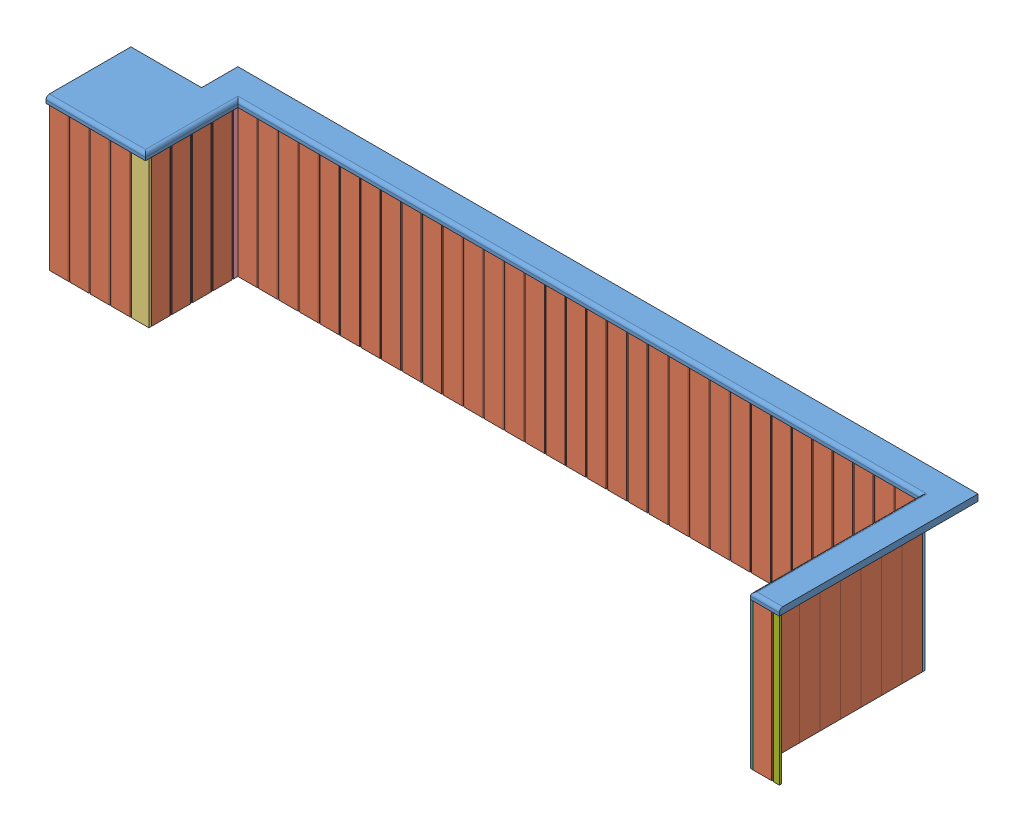
SolidWorks assembly Brüstung, configuration Standard. Lengths in mm.
Overall size (4774 900 1170).
56 component instances, 7 part files, 166 mates.
Components (placement in the parent):
- Platte-1: Platte [Standard] at (1989.1315 795.0064 4189) size (4774 38 1170)
- Wandbrett-1: Wandbrett [Standard] at (-2724.3685 795.0064 4876) x (1 0 0) z (0 0 -1) size (131 862 14)
- Wandbrett-2: Wandbrett [Standard] at (-2603.3685 795.0064 4876) x (1 0 0) z (0 0 -1) size (131 862 14)
- Wandbrett-3: Wandbrett [Standard] at (-2482.3685 795.0064 4876) x (1 0 0) z (0 0 -1) size (131 862 14)
- Wandbrett-4: Wandbrett [Standard] at (-2361.3685 795.0064 4876) x (1 0 0) z (0 0 -1) size (131 862 14)
- Wandbrett-Ecke1-1: Wandbrett-Ecke1 [Standard] at (-2240.3685 795.0064 4876) x (1 0 0) z (0 0 -1) size (102 862 14)
- Wandbrett-6: Wandbrett [Standard] at (-2205.8685 795.0064 4808.5) x (0 0 -1) z (-1 0 0) size (131 862 14)
- Wandbrett-7: Wandbrett [Standard] at (-2205.8685 795.0064 4687.5) x (0 0 -1) z (-1 0 0) size (131 862 14)
- Wandbrett-8: Wandbrett [Standard] at (-2205.8685 795.0064 4566.5) x (0 0 -1) z (-1 0 0) size (131 862 14)
- Wandbrett-9: Wandbrett [Standard] at (-2205.8685 795.0064 4445.5) x (0 0 -1) z (-1 0 0) size (131 862 14)
- Wandbrett-Ecke2-1: Wandbrett-Ecke2 [Standard] at (-2205.8685 795.0064 4324.5) x (0 0 -1) z (-1 0 0) size (60 862 14)
- Wandbrett-11: Wandbrett [Standard] at (-2138.3685 795.0064 4352) x (1 0 0) z (0 0 -1) size (131 862 14)
- Wandbrett-12: Wandbrett [Standard] at (-2017.3685 795.0064 4352) x (1 0 0) z (0 0 -1) size (131 862 14)
- Wandbrett-13: Wandbrett [Standard] at (-1896.3685 795.0064 4352) x (1 0 0) z (0 0 -1) size (131 862 14)
- Wandbrett-14: Wandbrett [Standard] at (-1775.3685 795.0064 4352) x (1 0 0) z (0 0 -1) size (131 862 14)
- Wandbrett-15: Wandbrett [Standard] at (-1654.3685 795.0064 4352) x (1 0 0) z (0 0 -1) size (131 862 14)
- Wandbrett-16: Wandbrett [Standard] at (-1533.3685 795.0064 4352) x (1 0 0) z (0 0 -1) size (131 862 14)
- Wandbrett-17: Wandbrett [Standard] at (-1412.3685 795.0064 4352) x (1 0 0) z (0 0 -1) size (131 862 14)
- Wandbrett-18: Wandbrett [Standard] at (-1291.3685 795.0064 4352) x (1 0 0) z (0 0 -1) size (131 862 14)
- Wandbrett-19: Wandbrett [Standard] at (-1170.3685 795.0064 4352) x (1 0 0) z (0 0 -1) size (131 862 14)
- Wandbrett-20: Wandbrett [Standard] at (-1049.3685 795.0064 4352) x (1 0 0) z (0 0 -1) size (131 862 14)
- Wandbrett-21: Wandbrett [Standard] at (-928.3685 795.0064 4352) x (1 0 0) z (0 0 -1) size (131 862 14)
- Wandbrett-22: Wandbrett [Standard] at (-807.3685 795.0064 4352) x (1 0 0) z (0 0 -1) size (131 862 14)
- Wandbrett-23: Wandbrett [Standard] at (-686.3685 795.0064 4352) x (1 0 0) z (0 0 -1) size (131 862 14)
- Wandbrett-24: Wandbrett [Standard] at (-565.3685 795.0064 4352) x (1 0 0) z (0 0 -1) size (131 862 14)
- Wandbrett-25: Wandbrett [Standard] at (-444.3685 795.0064 4352) x (1 0 0) z (0 0 -1) size (131 862 14)
- Wandbrett-26: Wandbrett [Standard] at (-323.3685 795.0064 4352) x (1 0 0) z (0 0 -1) size (131 862 14)
- Wandbrett-27: Wandbrett [Standard] at (-202.3685 795.0064 4352) x (1 0 0) z (0 0 -1) size (131 862 14)
- Wandbrett-28: Wandbrett [Standard] at (-81.3685 795.0064 4352) x (1 0 0) z (0 0 -1) size (131 862 14)
- Wandbrett-29: Wandbrett [Standard] at (39.6315 795.0064 4352) x (1 0 0) z (0 0 -1) size (131 862 14)
- Wandbrett-30: Wandbrett [Standard] at (160.6315 795.0064 4352) x (1 0 0) z (0 0 -1) size (131 862 14)
- Wandbrett-31: Wandbrett [Standard] at (281.6315 795.0064 4352) x (1 0 0) z (0 0 -1) size (131 862 14)
- Wandbrett-32: Wandbrett [Standard] at (402.6315 795.0064 4352) x (1 0 0) z (0 0 -1) size (131 862 14)
- Wandbrett-33: Wandbrett [Standard] at (523.6315 795.0064 4352) x (1 0 0) z (0 0 -1) size (131 862 14)
- Wandbrett-34: Wandbrett [Standard] at (644.6315 795.0064 4352) x (1 0 0) z (0 0 -1) size (131 862 14)
- Wandbrett-35: Wandbrett [Standard] at (765.6315 795.0064 4352) x (1 0 0) z (0 0 -1) size (131 862 14)
- Wandbrett-36: Wandbrett [Standard] at (886.6315 795.0064 4352) x (1 0 0) z (0 0 -1) size (131 862 14)
- Wandbrett-37: Wandbrett [Standard] at (1007.6315 795.0064 4352) x (1 0 0) z (0 0 -1) size (131 862 14)
- Wandbrett-38: Wandbrett [Standard] at (1128.6315 795.0064 4352) x (1 0 0) z (0 0 -1) size (131 862 14)
- Wandbrett-39: Wandbrett [Standard] at (1249.6315 795.0064 4352) x (1 0 0) z (0 0 -1) size (131 862 14)
- Wandbrett-40: Wandbrett [Standard] at (1370.6315 795.0064 4352) x (1 0 0) z (0 0 -1) size (131 862 14)
- Wandbrett-41: Wandbrett [Standard] at (1491.6315 795.0064 4352) x (1 0 0) z (0 0 -1) size (131 862 14)
- Wandbrett-42: Wandbrett [Standard] at (1612.6315 795.0064 4352) x (1 0 0) z (0 0 -1) size (131 862 14)
- Wandbrett-43: Wandbrett [Standard] at (1733.6315 795.0064 4352) x (1 0 0) z (0 0 -1) size (131 862 14)
- Wandbrett-Ecke3-1: Wandbrett-Ecke3 [Standard] at (1854.6315 795.0064 4352) x (1 0 0) z (0 0 -1) size (39 862 14)
- Wandbrett-44: Wandbrett [Standard] at (1826.1315 795.0064 4419.5) x (0 0 1) z (1 0 0) size (131 862 14)
- Wandbrett-45: Wandbrett [Standard] at (1826.1315 795.0064 4540.5) x (0 0 1) z (1 0 0) size (131 862 14)
- Wandbrett-46: Wandbrett [Standard] at (1826.1315 795.0064 4661.5) x (0 0 1) z (1 0 0) size (131 862 14)
- Wandbrett-47: Wandbrett [Standard] at (1826.1315 795.0064 4782.5) x (0 0 1) z (1 0 0) size (131 862 14)
- Wandbrett-48: Wandbrett [Standard] at (1826.1315 795.0064 4903.5) x (0 0 1) z (1 0 0) size (131 862 14)
- Wandbrett-49: Wandbrett [Standard] at (1826.1315 795.0064 5024.5) x (0 0 1) z (1 0 0) size (131 862 14)
- Wandbrett-50: Wandbrett [Standard] at (1826.1315 795.0064 5145.5) x (0 0 1) z (1 0 0) size (131 862 14)
- Wandbrett-51: Wandbrett [Standard] at (1826.1315 795.0064 5266.5) x (0 0 1) z (1 0 0) size (131 862 14)
- Wandbrett-Ecke4-1: Wandbrett-Ecke4 [Standard] at (1826.1315 795.0064 5387.5) x (0 0 1) z (1 0 0) size (32 862 14)
- Wandbrett-52: Wandbrett [Standard] at (1893.6315 795.0064 5352) x (1 0 0) z (0 0 -1) size (131 862 14)
- Wandbrett-Ecke5-1: Wandbrett-Ecke5 [Standard] at (2014.6315 795.0064 5352) x (1 0 0) z (0 0 -1) size (35 862 14)
Mates (geometry in assembly coordinates):
- Deckungsgleich1: coincident anti-aligned: plane of Platte-1 through (1989.1315 795.0064 4189) normal (0 -1 0); plane of Wandbrett-1 through (-2674.8685 795.0064 4879) normal (0 1 0)
- Deckungsgleich2: coincident anti-aligned: plane of Platte-1 through (1989.1315 795.0064 4189) normal (0 -1 0); plane of Wandbrett-2 through (-2553.8685 795.0064 4879) normal (0 1 0)
- Deckungsgleich3: coincident anti-aligned: plane of Platte-1 through (1989.1315 795.0064 4189) normal (0 -1 0); plane of Wandbrett-3 through (-2432.8685 795.0064 4879) normal (0 1 0)
- Deckungsgleich4: coincident anti-aligned: plane of Platte-1 through (1989.1315 795.0064 4189) normal (0 -1 0); plane of Wandbrett-4 through (-2311.8685 795.0064 4879) normal (0 1 0)
- Parallel1: parallel aligned: plane of Platte-1 through (-2784.8685 833.0064 4903) normal (0 0 1); plane of Wandbrett-1 through (-2674.8685 -66.9936 4883) normal (0 0 1)
- Abstand2: distance = 20 mm aligned: plane of Wandbrett-1 through (-2674.8685 -66.9936 4883) normal (0 0 1); plane of Platte-1 through (-2784.8685 833.0064 4903) normal (0 0 1)
- Deckungsgleich9: coincident aligned: plane of Platte-1 through (-2784.8685 833.0064 4903) normal (-1 0 0); plane of Wandbrett-1 through (-2784.8685 -66.9936 4869) normal (-1 0 0)
- Deckungsgleich10: coincident anti-aligned: plane of Wandbrett-1 through (-2663.8685 -66.9936 4878) normal (0 0 1); plane of Wandbrett-2 through (-2653.8685 -66.9936 4878) normal (0 0 -1)
- Deckungsgleich11: coincident anti-aligned: plane of Wandbrett-2 through (-2542.8685 -66.9936 4878) normal (0 0 1); plane of Wandbrett-3 through (-2532.8685 -66.9936 4878) normal (0 0 -1)
- Deckungsgleich12: coincident anti-aligned: plane of Wandbrett-3 through (-2421.8685 -66.9936 4878) normal (0 0 1); plane of Wandbrett-4 through (-2411.8685 -66.9936 4878) normal (0 0 -1)
- Deckungsgleich14: coincident anti-aligned: plane of Wandbrett-1 through (-2653.8685 -66.9936 4878) normal (1 0 0); plane of Wandbrett-2 through (-2653.8685 -66.9936 4874) normal (-1 0 0)
- Deckungsgleich15: coincident anti-aligned: plane of Wandbrett-2 through (-2532.8685 -66.9936 4878) normal (1 0 0); plane of Wandbrett-3 through (-2532.8685 -66.9936 4874) normal (-1 0 0)
- Deckungsgleich16: coincident anti-aligned: plane of Wandbrett-3 through (-2411.8685 -66.9936 4878) normal (1 0 0); plane of Wandbrett-4 through (-2411.8685 -66.9936 4874) normal (-1 0 0)
- Deckungsgleich18: coincident anti-aligned: plane of Platte-1 through (1989.1315 795.0064 4189) normal (0 -1 0); plane of Wandbrett-Ecke1-1 through (-2190.8685 795.0064 4879) normal (0 1 0)
- Deckungsgleich19: coincident anti-aligned: plane of Wandbrett-4 through (-2300.8685 -66.9936 4878) normal (0 0 1); plane of Wandbrett-Ecke1-1 through (-2290.8685 -66.9936 4878) normal (0 0 -1)
- Deckungsgleich20: coincident anti-aligned: plane of Wandbrett-4 through (-2290.8685 -66.9936 4878) normal (1 0 0); plane of Wandbrett-Ecke1-1 through (-2290.8685 -66.9936 4874) normal (-1 0 0)
- Deckungsgleich21: coincident anti-aligned: plane of Platte-1 through (1989.1315 795.0064 4189) normal (0 -1 0); plane of Wandbrett-6 through (-2202.8685 795.0064 4759) normal (0 1 0)
- Deckungsgleich22: coincident anti-aligned: plane of Platte-1 through (1989.1315 795.0064 4189) normal (0 -1 0); plane of Wandbrett-7 through (-2202.8685 795.0064 4638) normal (0 1 0)
- Deckungsgleich23: coincident anti-aligned: plane of Platte-1 through (1989.1315 795.0064 4189) normal (0 -1 0); plane of Wandbrett-8 through (-2202.8685 795.0064 4517) normal (0 1 0)
- Deckungsgleich24: coincident anti-aligned: plane of Platte-1 through (1989.1315 795.0064 4189) normal (0 -1 0); plane of Wandbrett-9 through (-2202.8685 795.0064 4396) normal (0 1 0)
- Deckungsgleich26: coincident anti-aligned: plane of Wandbrett-Ecke1-1 through (-2179.8685 -66.9936 4869) normal (0 0 -1); plane of Wandbrett-6 through (-2212.8685 -66.9936 4869) normal (0 0 1)
- Deckungsgleich27: coincident aligned: plane of Platte-1 through (-2198.8685 833.0064 4359) normal (1 0 0); plane of Wandbrett-6 through (-2198.8685 -66.9936 4759) normal (1 0 0)
- Deckungsgleich28: coincident anti-aligned: plane of Wandbrett-6 through (-2203.8685 -66.9936 4748) normal (1 0 0); plane of Wandbrett-7 through (-2203.8685 -66.9936 4738) normal (-1 0 0)
- Deckungsgleich29: coincident anti-aligned: plane of Wandbrett-7 through (-2203.8685 -66.9936 4627) normal (1 0 0); plane of Wandbrett-8 through (-2203.8685 -66.9936 4617) normal (-1 0 0)
- Deckungsgleich30: coincident anti-aligned: plane of Wandbrett-8 through (-2203.8685 -66.9936 4506) normal (1 0 0); plane of Wandbrett-9 through (-2203.8685 -66.9936 4496) normal (-1 0 0)
- Deckungsgleich32: coincident anti-aligned: plane of Wandbrett-6 through (-2203.8685 -66.9936 4738) normal (0 0 -1); plane of Wandbrett-7 through (-2207.8685 -66.9936 4738) normal (0 0 1)
- Deckungsgleich33: coincident anti-aligned: plane of Wandbrett-7 through (-2203.8685 -66.9936 4617) normal (0 0 -1); plane of Wandbrett-8 through (-2207.8685 -66.9936 4617) normal (0 0 1)
- Deckungsgleich34: coincident anti-aligned: plane of Wandbrett-8 through (-2203.8685 -66.9936 4496) normal (0 0 -1); plane of Wandbrett-9 through (-2207.8685 -66.9936 4496) normal (0 0 1)
- Deckungsgleich36: coincident anti-aligned: plane of Platte-1 through (1989.1315 795.0064 4189) normal (0 -1 0); plane of Wandbrett-Ecke2-1 through (-2202.8685 795.0064 4275) normal (0 1 0)
- Deckungsgleich37: coincident anti-aligned: plane of Wandbrett-9 through (-2203.8685 -66.9936 4385) normal (1 0 0); plane of Wandbrett-Ecke2-1 through (-2203.8685 -66.9936 4375) normal (-1 0 0)
- Deckungsgleich38: coincident anti-aligned: plane of Wandbrett-9 through (-2203.8685 -66.9936 4375) normal (0 0 -1); plane of Wandbrett-Ecke2-1 through (-2207.8685 -66.9936 4375) normal (0 0 1)
- Deckungsgleich39: coincident anti-aligned: plane of Platte-1 through (1989.1315 795.0064 4189) normal (0 -1 0); plane of Wandbrett-11 through (-2088.8685 795.0064 4355) normal (0 1 0)
- Deckungsgleich40: coincident anti-aligned: plane of Platte-1 through (1989.1315 795.0064 4189) normal (0 -1 0); plane of Wandbrett-12 through (-1967.8685 795.0064 4355) normal (0 1 0)
- Deckungsgleich41: coincident anti-aligned: plane of Platte-1 through (1989.1315 795.0064 4189) normal (0 -1 0); plane of Wandbrett-13 through (-1846.8685 795.0064 4355) normal (0 1 0)
- Deckungsgleich42: coincident anti-aligned: plane of Platte-1 through (1989.1315 795.0064 4189) normal (0 -1 0); plane of Wandbrett-14 through (-1725.8685 795.0064 4355) normal (0 1 0)
- Deckungsgleich43: coincident anti-aligned: plane of Platte-1 through (1989.1315 795.0064 4189) normal (0 -1 0); plane of Wandbrett-15 through (-1604.8685 795.0064 4355) normal (0 1 0)
- Deckungsgleich44: coincident anti-aligned: plane of Platte-1 through (1989.1315 795.0064 4189) normal (0 -1 0); plane of Wandbrett-16 through (-1483.8685 795.0064 4355) normal (0 1 0)
- Deckungsgleich45: coincident anti-aligned: plane of Platte-1 through (1989.1315 795.0064 4189) normal (0 -1 0); plane of Wandbrett-17 through (-1362.8685 795.0064 4355) normal (0 1 0)
- Deckungsgleich46: coincident anti-aligned: plane of Platte-1 through (1989.1315 795.0064 4189) normal (0 -1 0); plane of Wandbrett-18 through (-1241.8685 795.0064 4355) normal (0 1 0)
- Deckungsgleich47: coincident anti-aligned: plane of Platte-1 through (1989.1315 795.0064 4189) normal (0 -1 0); plane of Wandbrett-19 through (-1120.8685 795.0064 4355) normal (0 1 0)
- Deckungsgleich48: coincident anti-aligned: plane of Platte-1 through (1989.1315 795.0064 4189) normal (0 -1 0); plane of Wandbrett-20 through (-999.8685 795.0064 4355) normal (0 1 0)
- Deckungsgleich49: coincident anti-aligned: plane of Platte-1 through (1989.1315 795.0064 4189) normal (0 -1 0); plane of Wandbrett-21 through (-878.8685 795.0064 4355) normal (0 1 0)
- Deckungsgleich50: coincident anti-aligned: plane of Platte-1 through (1989.1315 795.0064 4189) normal (0 -1 0); plane of Wandbrett-22 through (-757.8685 795.0064 4355) normal (0 1 0)
- Deckungsgleich51: coincident anti-aligned: plane of Platte-1 through (1989.1315 795.0064 4189) normal (0 -1 0); plane of Wandbrett-23 through (-636.8685 795.0064 4355) normal (0 1 0)
- Deckungsgleich52: coincident anti-aligned: plane of Platte-1 through (1989.1315 795.0064 4189) normal (0 -1 0); plane of Wandbrett-24 through (-515.8685 795.0064 4355) normal (0 1 0)
- Deckungsgleich53: coincident anti-aligned: plane of Platte-1 through (1989.1315 795.0064 4189) normal (0 -1 0); plane of Wandbrett-25 through (-394.8685 795.0064 4355) normal (0 1 0)
- Deckungsgleich54: coincident anti-aligned: plane of Platte-1 through (1989.1315 795.0064 4189) normal (0 -1 0); plane of Wandbrett-26 through (-273.8685 795.0064 4355) normal (0 1 0)
- Deckungsgleich55: coincident anti-aligned: plane of Platte-1 through (1989.1315 795.0064 4189) normal (0 -1 0); plane of Wandbrett-27 through (-152.8685 795.0064 4355) normal (0 1 0)
- Deckungsgleich56: coincident anti-aligned: plane of Platte-1 through (1989.1315 795.0064 4189) normal (0 -1 0); plane of Wandbrett-28 through (-31.8685 795.0064 4355) normal (0 1 0)
- Deckungsgleich57: coincident anti-aligned: plane of Platte-1 through (1989.1315 795.0064 4189) normal (0 -1 0); plane of Wandbrett-29 through (89.1315 795.0064 4355) normal (0 1 0)
- Deckungsgleich58: coincident anti-aligned: plane of Platte-1 through (1989.1315 795.0064 4189) normal (0 -1 0); plane of Wandbrett-30 through (210.1315 795.0064 4355) normal (0 1 0)
- Deckungsgleich59: coincident anti-aligned: plane of Platte-1 through (1989.1315 795.0064 4189) normal (0 -1 0); plane of Wandbrett-31 through (331.1315 795.0064 4355) normal (0 1 0)
- Deckungsgleich60: coincident anti-aligned: plane of Platte-1 through (1989.1315 795.0064 4189) normal (0 -1 0); plane of Wandbrett-32 through (452.1315 795.0064 4355) normal (0 1 0)
- Deckungsgleich61: coincident anti-aligned: plane of Platte-1 through (1989.1315 795.0064 4189) normal (0 -1 0); plane of Wandbrett-33 through (573.1315 795.0064 4355) normal (0 1 0)
- Deckungsgleich62: coincident anti-aligned: plane of Platte-1 through (1989.1315 795.0064 4189) normal (0 -1 0); plane of Wandbrett-34 through (694.1315 795.0064 4355) normal (0 1 0)
- Deckungsgleich63: coincident anti-aligned: plane of Platte-1 through (1989.1315 795.0064 4189) normal (0 -1 0); plane of Wandbrett-35 through (815.1315 795.0064 4355) normal (0 1 0)
- Deckungsgleich64: coincident anti-aligned: plane of Platte-1 through (1989.1315 795.0064 4189) normal (0 -1 0); plane of Wandbrett-36 through (936.1315 795.0064 4355) normal (0 1 0)
- Deckungsgleich65: coincident anti-aligned: plane of Platte-1 through (1989.1315 795.0064 4189) normal (0 -1 0); plane of Wandbrett-37 through (1057.1315 795.0064 4355) normal (0 1 0)
- Deckungsgleich66: coincident anti-aligned: plane of Platte-1 through (1989.1315 795.0064 4189) normal (0 -1 0); plane of Wandbrett-38 through (1178.1315 795.0064 4355) normal (0 1 0)
- Deckungsgleich67: coincident anti-aligned: plane of Platte-1 through (1989.1315 795.0064 4189) normal (0 -1 0); plane of Wandbrett-39 through (1299.1315 795.0064 4355) normal (0 1 0)
- Deckungsgleich68: coincident anti-aligned: plane of Platte-1 through (1989.1315 795.0064 4189) normal (0 -1 0); plane of Wandbrett-40 through (1420.1315 795.0064 4355) normal (0 1 0)
- Deckungsgleich69: coincident anti-aligned: plane of Platte-1 through (1989.1315 795.0064 4189) normal (0 -1 0); plane of Wandbrett-41 through (1541.1315 795.0064 4355) normal (0 1 0)
- Deckungsgleich70: coincident anti-aligned: plane of Platte-1 through (1989.1315 795.0064 4189) normal (0 -1 0); plane of Wandbrett-42 through (1662.1315 795.0064 4355) normal (0 1 0)
- Deckungsgleich71: coincident anti-aligned: plane of Wandbrett-Ecke2-1 through (-2198.8685 -66.9936 4275) normal (1 0 0); plane of Wandbrett-11 through (-2198.8685 -66.9936 4354) normal (-1 0 0)
- Deckungsgleich72: coincident anti-aligned: plane of Wandbrett-11 through (-2077.8685 -66.9936 4354) normal (0 0 1); plane of Wandbrett-12 through (-2067.8685 -66.9936 4354) normal (0 0 -1)
- Deckungsgleich73: coincident anti-aligned: plane of Wandbrett-12 through (-1956.8685 -66.9936 4354) normal (0 0 1); plane of Wandbrett-13 through (-1946.8685 -66.9936 4354) normal (0 0 -1)
- Deckungsgleich74: coincident anti-aligned: plane of Wandbrett-13 through (-1835.8685 -66.9936 4354) normal (0 0 1); plane of Wandbrett-14 through (-1825.8685 -66.9936 4354) normal (0 0 -1)
- Deckungsgleich75: coincident anti-aligned: plane of Wandbrett-14 through (-1714.8685 -66.9936 4354) normal (0 0 1); plane of Wandbrett-15 through (-1704.8685 -66.9936 4354) normal (0 0 -1)
- Deckungsgleich76: coincident anti-aligned: plane of Wandbrett-15 through (-1593.8685 -66.9936 4354) normal (0 0 1); plane of Wandbrett-16 through (-1583.8685 -66.9936 4354) normal (0 0 -1)
- Deckungsgleich77: coincident anti-aligned: plane of Wandbrett-16 through (-1472.8685 -66.9936 4354) normal (0 0 1); plane of Wandbrett-17 through (-1462.8685 -66.9936 4354) normal (0 0 -1)
- Deckungsgleich78: coincident anti-aligned: plane of Wandbrett-17 through (-1351.8685 -66.9936 4354) normal (0 0 1); plane of Wandbrett-18 through (-1341.8685 -66.9936 4354) normal (0 0 -1)
- Deckungsgleich79: coincident anti-aligned: plane of Wandbrett-18 through (-1230.8685 -66.9936 4354) normal (0 0 1); plane of Wandbrett-19 through (-1220.8685 -66.9936 4354) normal (0 0 -1)
- Deckungsgleich80: coincident anti-aligned: plane of Wandbrett-19 through (-1109.8685 -66.9936 4354) normal (0 0 1); plane of Wandbrett-20 through (-1099.8685 -66.9936 4354) normal (0 0 -1)
- Deckungsgleich81: coincident anti-aligned: plane of Wandbrett-20 through (-988.8685 -66.9936 4354) normal (0 0 1); plane of Wandbrett-21 through (-978.8685 -66.9936 4354) normal (0 0 -1)
- Deckungsgleich82: coincident anti-aligned: plane of Wandbrett-21 through (-867.8685 -66.9936 4354) normal (0 0 1); plane of Wandbrett-22 through (-857.8685 -66.9936 4354) normal (0 0 -1)
- Deckungsgleich83: coincident anti-aligned: plane of Wandbrett-22 through (-746.8685 -66.9936 4354) normal (0 0 1); plane of Wandbrett-23 through (-736.8685 -66.9936 4354) normal (0 0 -1)
- Deckungsgleich84: coincident anti-aligned: plane of Wandbrett-23 through (-625.8685 -66.9936 4354) normal (0 0 1); plane of Wandbrett-24 through (-615.8685 -66.9936 4354) normal (0 0 -1)
- Deckungsgleich85: coincident anti-aligned: plane of Wandbrett-24 through (-504.8685 -66.9936 4354) normal (0 0 1); plane of Wandbrett-25 through (-494.8685 -66.9936 4354) normal (0 0 -1)
- Deckungsgleich86: coincident anti-aligned: plane of Wandbrett-25 through (-383.8685 -66.9936 4354) normal (0 0 1); plane of Wandbrett-26 through (-373.8685 -66.9936 4354) normal (0 0 -1)
- Deckungsgleich87: coincident anti-aligned: plane of Wandbrett-26 through (-262.8685 -66.9936 4354) normal (0 0 1); plane of Wandbrett-27 through (-252.8685 -66.9936 4354) normal (0 0 -1)
- Deckungsgleich88: coincident anti-aligned: plane of Wandbrett-27 through (-141.8685 -66.9936 4354) normal (0 0 1); plane of Wandbrett-28 through (-131.8685 -66.9936 4354) normal (0 0 -1)
- Deckungsgleich90: coincident anti-aligned: plane of Wandbrett-28 through (-20.8685 -66.9936 4354) normal (0 0 1); plane of Wandbrett-29 through (-10.8685 -66.9936 4354) normal (0 0 -1)
- Deckungsgleich91: coincident anti-aligned: plane of Wandbrett-29 through (100.1315 -66.9936 4354) normal (0 0 1); plane of Wandbrett-30 through (110.1315 -66.9936 4354) normal (0 0 -1)
- Deckungsgleich92: coincident anti-aligned: plane of Wandbrett-30 through (221.1315 -66.9936 4354) normal (0 0 1); plane of Wandbrett-31 through (231.1315 -66.9936 4354) normal (0 0 -1)
- Deckungsgleich93: coincident anti-aligned: plane of Wandbrett-31 through (342.1315 -66.9936 4354) normal (0 0 1); plane of Wandbrett-32 through (352.1315 -66.9936 4354) normal (0 0 -1)
- Deckungsgleich94: coincident anti-aligned: plane of Wandbrett-32 through (463.1315 -66.9936 4354) normal (0 0 1); plane of Wandbrett-33 through (473.1315 -66.9936 4354) normal (0 0 -1)
- Deckungsgleich95: coincident anti-aligned: plane of Wandbrett-33 through (584.1315 -66.9936 4354) normal (0 0 1); plane of Wandbrett-34 through (594.1315 -66.9936 4354) normal (0 0 -1)
- Deckungsgleich96: coincident anti-aligned: plane of Wandbrett-34 through (705.1315 -66.9936 4354) normal (0 0 1); plane of Wandbrett-35 through (715.1315 -66.9936 4354) normal (0 0 -1)
- Deckungsgleich97: coincident anti-aligned: plane of Wandbrett-35 through (826.1315 -66.9936 4354) normal (0 0 1); plane of Wandbrett-36 through (836.1315 -66.9936 4354) normal (0 0 -1)
- Deckungsgleich98: coincident anti-aligned: plane of Wandbrett-36 through (947.1315 -66.9936 4354) normal (0 0 1); plane of Wandbrett-37 through (957.1315 -66.9936 4354) normal (0 0 -1)
- Deckungsgleich99: coincident anti-aligned: plane of Wandbrett-37 through (1068.1315 -66.9936 4354) normal (0 0 1); plane of Wandbrett-38 through (1078.1315 -66.9936 4354) normal (0 0 -1)
- Deckungsgleich100: coincident anti-aligned: plane of Wandbrett-38 through (1189.1315 -66.9936 4354) normal (0 0 1); plane of Wandbrett-39 through (1199.1315 -66.9936 4354) normal (0 0 -1)
- Deckungsgleich101: coincident anti-aligned: plane of Wandbrett-39 through (1310.1315 -66.9936 4354) normal (0 0 1); plane of Wandbrett-40 through (1320.1315 -66.9936 4354) normal (0 0 -1)
- Deckungsgleich102: coincident anti-aligned: plane of Wandbrett-40 through (1431.1315 -66.9936 4354) normal (0 0 1); plane of Wandbrett-41 through (1441.1315 -66.9936 4354) normal (0 0 -1)
- Deckungsgleich103: coincident anti-aligned: plane of Wandbrett-41 through (1552.1315 -66.9936 4354) normal (0 0 1); plane of Wandbrett-42 through (1562.1315 -66.9936 4354) normal (0 0 -1)
- Deckungsgleich104: coincident aligned: plane of Platte-1 through (-2198.8685 833.0064 4359) normal (0 0 1); plane of Wandbrett-11 through (-2088.8685 -66.9936 4359) normal (0 0 1)
- Deckungsgleich105: coincident anti-aligned: plane of Wandbrett-11 through (-2067.8685 -66.9936 4354) normal (1 0 0); plane of Wandbrett-12 through (-2067.8685 -66.9936 4350) normal (-1 0 0)
- Deckungsgleich106: coincident anti-aligned: plane of Wandbrett-12 through (-1946.8685 -66.9936 4354) normal (1 0 0); plane of Wandbrett-13 through (-1946.8685 -66.9936 4350) normal (-1 0 0)
- Deckungsgleich107: coincident anti-aligned: plane of Wandbrett-13 through (-1825.8685 -66.9936 4354) normal (1 0 0); plane of Wandbrett-14 through (-1825.8685 -66.9936 4350) normal (-1 0 0)
- Deckungsgleich108: coincident anti-aligned: plane of Wandbrett-14 through (-1704.8685 -66.9936 4354) normal (1 0 0); plane of Wandbrett-15 through (-1704.8685 -66.9936 4350) normal (-1 0 0)
- Deckungsgleich109: coincident anti-aligned: plane of Wandbrett-15 through (-1583.8685 -66.9936 4354) normal (1 0 0); plane of Wandbrett-16 through (-1583.8685 -66.9936 4350) normal (-1 0 0)
- Deckungsgleich110: coincident anti-aligned: plane of Wandbrett-16 through (-1462.8685 -66.9936 4354) normal (1 0 0); plane of Wandbrett-17 through (-1462.8685 -66.9936 4350) normal (-1 0 0)
- Deckungsgleich111: coincident anti-aligned: plane of Wandbrett-17 through (-1341.8685 -66.9936 4354) normal (1 0 0); plane of Wandbrett-18 through (-1341.8685 -66.9936 4350) normal (-1 0 0)
- Deckungsgleich112: coincident anti-aligned: plane of Wandbrett-18 through (-1220.8685 -66.9936 4354) normal (1 0 0); plane of Wandbrett-19 through (-1220.8685 -66.9936 4350) normal (-1 0 0)
- Deckungsgleich113: coincident anti-aligned: plane of Wandbrett-19 through (-1099.8685 -66.9936 4354) normal (1 0 0); plane of Wandbrett-20 through (-1099.8685 -66.9936 4350) normal (-1 0 0)
- Deckungsgleich114: coincident anti-aligned: plane of Wandbrett-20 through (-978.8685 -66.9936 4354) normal (1 0 0); plane of Wandbrett-21 through (-978.8685 -66.9936 4350) normal (-1 0 0)
- Deckungsgleich115: coincident anti-aligned: plane of Wandbrett-21 through (-857.8685 -66.9936 4354) normal (1 0 0); plane of Wandbrett-22 through (-857.8685 -66.9936 4350) normal (-1 0 0)
- Deckungsgleich117: coincident anti-aligned: plane of Wandbrett-22 through (-736.8685 -66.9936 4354) normal (1 0 0); plane of Wandbrett-23 through (-736.8685 -66.9936 4350) normal (-1 0 0)
- Deckungsgleich118: coincident anti-aligned: plane of Wandbrett-23 through (-615.8685 -66.9936 4354) normal (1 0 0); plane of Wandbrett-24 through (-615.8685 -66.9936 4350) normal (-1 0 0)
- Deckungsgleich119: coincident anti-aligned: plane of Wandbrett-24 through (-494.8685 -66.9936 4354) normal (1 0 0); plane of Wandbrett-25 through (-494.8685 -66.9936 4350) normal (-1 0 0)
- Deckungsgleich121: coincident anti-aligned: plane of Wandbrett-25 through (-373.8685 -66.9936 4354) normal (1 0 0); plane of Wandbrett-26 through (-373.8685 -66.9936 4350) normal (-1 0 0)
- Deckungsgleich122: coincident anti-aligned: plane of Wandbrett-26 through (-252.8685 -66.9936 4354) normal (1 0 0); plane of Wandbrett-27 through (-252.8685 -66.9936 4350) normal (-1 0 0)
- Deckungsgleich123: coincident anti-aligned: plane of Wandbrett-27 through (-131.8685 -66.9936 4354) normal (1 0 0); plane of Wandbrett-28 through (-131.8685 -66.9936 4350) normal (-1 0 0)
- Deckungsgleich124: coincident anti-aligned: plane of Wandbrett-28 through (-10.8685 -66.9936 4354) normal (1 0 0); plane of Wandbrett-29 through (-10.8685 -66.9936 4350) normal (-1 0 0)
- Deckungsgleich125: coincident anti-aligned: plane of Wandbrett-29 through (110.1315 -66.9936 4354) normal (1 0 0); plane of Wandbrett-30 through (110.1315 -66.9936 4350) normal (-1 0 0)
- Deckungsgleich126: coincident anti-aligned: plane of Wandbrett-30 through (231.1315 -66.9936 4354) normal (1 0 0); plane of Wandbrett-31 through (231.1315 -66.9936 4350) normal (-1 0 0)
- Deckungsgleich127: coincident anti-aligned: plane of Wandbrett-31 through (352.1315 -66.9936 4354) normal (1 0 0); plane of Wandbrett-32 through (352.1315 -66.9936 4350) normal (-1 0 0)
- Deckungsgleich128: coincident anti-aligned: plane of Wandbrett-32 through (473.1315 -66.9936 4354) normal (1 0 0); plane of Wandbrett-33 through (473.1315 -66.9936 4350) normal (-1 0 0)
- Deckungsgleich129: coincident anti-aligned: plane of Wandbrett-33 through (594.1315 -66.9936 4354) normal (1 0 0); plane of Wandbrett-34 through (594.1315 -66.9936 4350) normal (-1 0 0)
- Deckungsgleich130: coincident anti-aligned: plane of Wandbrett-34 through (715.1315 -66.9936 4354) normal (1 0 0); plane of Wandbrett-35 through (715.1315 -66.9936 4350) normal (-1 0 0)
- Deckungsgleich131: coincident anti-aligned: plane of Wandbrett-35 through (836.1315 -66.9936 4354) normal (1 0 0); plane of Wandbrett-36 through (836.1315 -66.9936 4350) normal (-1 0 0)
- Deckungsgleich132: coincident anti-aligned: plane of Wandbrett-36 through (957.1315 -66.9936 4354) normal (1 0 0); plane of Wandbrett-37 through (957.1315 -66.9936 4350) normal (-1 0 0)
- Deckungsgleich133: coincident anti-aligned: plane of Wandbrett-37 through (1078.1315 -66.9936 4354) normal (1 0 0); plane of Wandbrett-38 through (1078.1315 -66.9936 4350) normal (-1 0 0)
- Deckungsgleich136: coincident anti-aligned: plane of Wandbrett-38 through (1199.1315 -66.9936 4354) normal (1 0 0); plane of Wandbrett-39 through (1199.1315 -66.9936 4350) normal (-1 0 0)
- Deckungsgleich137: coincident anti-aligned: plane of Wandbrett-39 through (1320.1315 -66.9936 4354) normal (1 0 0); plane of Wandbrett-40 through (1320.1315 -66.9936 4350) normal (-1 0 0)
- Deckungsgleich138: coincident anti-aligned: plane of Wandbrett-40 through (1441.1315 -66.9936 4354) normal (1 0 0); plane of Wandbrett-41 through (1441.1315 -66.9936 4350) normal (-1 0 0)
- Deckungsgleich139: coincident anti-aligned: plane of Wandbrett-41 through (1562.1315 -66.9936 4354) normal (1 0 0); plane of Wandbrett-42 through (1562.1315 -66.9936 4350) normal (-1 0 0)
- Deckungsgleich140: coincident anti-aligned: plane of Platte-1 through (1989.1315 795.0064 4189) normal (0 -1 0); plane of Wandbrett-43 through (1783.1315 795.0064 4355) normal (0 1 0)
- Deckungsgleich141: coincident anti-aligned: plane of Wandbrett-42 through (1673.1315 -66.9936 4354) normal (0 0 1); plane of Wandbrett-43 through (1683.1315 -66.9936 4354) normal (0 0 -1)
- Deckungsgleich142: coincident anti-aligned: plane of Wandbrett-42 through (1683.1315 -66.9936 4354) normal (1 0 0); plane of Wandbrett-43 through (1683.1315 -66.9936 4350) normal (-1 0 0)
- Deckungsgleich143: coincident anti-aligned: plane of Platte-1 through (1989.1315 795.0064 4189) normal (0 -1 0); plane of Wandbrett-Ecke3-1 through (1904.1315 795.0064 4355) normal (0 1 0)
- Deckungsgleich144: coincident anti-aligned: plane of Wandbrett-43 through (1794.1315 -66.9936 4354) normal (0 0 1); plane of Wandbrett-Ecke3-1 through (1804.1315 -66.9936 4354) normal (0 0 -1)
- Deckungsgleich145: coincident anti-aligned: plane of Wandbrett-43 through (1804.1315 -66.9936 4354) normal (1 0 0); plane of Wandbrett-Ecke3-1 through (1804.1315 -66.9936 4350) normal (-1 0 0)
- Deckungsgleich156: coincident anti-aligned: plane of Platte-1 through (1989.1315 795.0064 4189) normal (0 -1 0); plane of Wandbrett-44 through (1823.1315 795.0064 4469) normal (0 1 0)
- Deckungsgleich157: coincident anti-aligned: plane of Platte-1 through (1989.1315 795.0064 4189) normal (0 -1 0); plane of Wandbrett-45 through (1823.1315 795.0064 4590) normal (0 1 0)
- Deckungsgleich158: coincident anti-aligned: plane of Platte-1 through (1989.1315 795.0064 4189) normal (0 -1 0); plane of Wandbrett-46 through (1823.1315 795.0064 4711) normal (0 1 0)
- Deckungsgleich159: coincident anti-aligned: plane of Platte-1 through (1989.1315 795.0064 4189) normal (0 -1 0); plane of Wandbrett-47 through (1823.1315 795.0064 4832) normal (0 1 0)
- Deckungsgleich160: coincident anti-aligned: plane of Platte-1 through (1989.1315 795.0064 4189) normal (0 -1 0); plane of Wandbrett-48 through (1823.1315 795.0064 4953) normal (0 1 0)
- Deckungsgleich161: coincident anti-aligned: plane of Platte-1 through (1989.1315 795.0064 4189) normal (0 -1 0); plane of Wandbrett-49 through (1823.1315 795.0064 5074) normal (0 1 0)
- Deckungsgleich162: coincident anti-aligned: plane of Platte-1 through (1989.1315 795.0064 4189) normal (0 -1 0); plane of Wandbrett-50 through (1823.1315 795.0064 5195) normal (0 1 0)
- Deckungsgleich163: coincident anti-aligned: plane of Platte-1 through (1989.1315 795.0064 4189) normal (0 -1 0); plane of Wandbrett-51 through (1823.1315 795.0064 5316) normal (0 1 0)
- Deckungsgleich164: coincident anti-aligned: plane of Wandbrett-Ecke3-1 through (1904.1315 -66.9936 4359) normal (0 0 1); plane of Wandbrett-44 through (1824.1315 -66.9936 4359) normal (0 0 -1)
- Deckungsgleich165: coincident aligned: plane of Platte-1 through (1819.1315 833.0064 4359) normal (-1 0 0); plane of Wandbrett-44 through (1819.1315 -66.9936 4469) normal (-1 0 0)
- Deckungsgleich166: coincident anti-aligned: plane of Wandbrett-44 through (1824.1315 -66.9936 4480) normal (-1 0 0); plane of Wandbrett-45 through (1824.1315 -66.9936 4490) normal (1 0 0)
- Deckungsgleich167: coincident anti-aligned: plane of Wandbrett-45 through (1824.1315 -66.9936 4601) normal (-1 0 0); plane of Wandbrett-46 through (1824.1315 -66.9936 4611) normal (1 0 0)
- Deckungsgleich168: coincident anti-aligned: plane of Wandbrett-46 through (1824.1315 -66.9936 4722) normal (-1 0 0); plane of Wandbrett-47 through (1824.1315 -66.9936 4732) normal (1 0 0)
- Deckungsgleich169: coincident anti-aligned: plane of Wandbrett-47 through (1824.1315 -66.9936 4843) normal (-1 0 0); plane of Wandbrett-48 through (1824.1315 -66.9936 4853) normal (1 0 0)
- Deckungsgleich170: coincident anti-aligned: plane of Wandbrett-48 through (1824.1315 -66.9936 4964) normal (-1 0 0); plane of Wandbrett-49 through (1824.1315 -66.9936 4974) normal (1 0 0)
- Deckungsgleich171: coincident anti-aligned: plane of Wandbrett-49 through (1824.1315 -66.9936 5085) normal (-1 0 0); plane of Wandbrett-50 through (1824.1315 -66.9936 5095) normal (1 0 0)
- Deckungsgleich172: coincident anti-aligned: plane of Wandbrett-50 through (1824.1315 -66.9936 5206) normal (-1 0 0); plane of Wandbrett-51 through (1824.1315 -66.9936 5216) normal (1 0 0)
- Deckungsgleich173: coincident anti-aligned: plane of Wandbrett-44 through (1824.1315 -66.9936 4490) normal (0 0 1); plane of Wandbrett-45 through (1828.1315 -66.9936 4490) normal (0 0 -1)
- Deckungsgleich174: coincident anti-aligned: plane of Wandbrett-45 through (1824.1315 -66.9936 4611) normal (0 0 1); plane of Wandbrett-46 through (1828.1315 -66.9936 4611) normal (0 0 -1)
- Deckungsgleich175: coincident anti-aligned: plane of Wandbrett-46 through (1824.1315 -66.9936 4732) normal (0 0 1); plane of Wandbrett-47 through (1828.1315 -66.9936 4732) normal (0 0 -1)
- Deckungsgleich176: coincident anti-aligned: plane of Wandbrett-47 through (1824.1315 -66.9936 4853) normal (0 0 1); plane of Wandbrett-48 through (1828.1315 -66.9936 4853) normal (0 0 -1)
- Deckungsgleich177: coincident anti-aligned: plane of Wandbrett-48 through (1824.1315 -66.9936 4974) normal (0 0 1); plane of Wandbrett-49 through (1828.1315 -66.9936 4974) normal (0 0 -1)
- Deckungsgleich179: coincident anti-aligned: plane of Wandbrett-49 through (1824.1315 -66.9936 5095) normal (0 0 1); plane of Wandbrett-50 through (1828.1315 -66.9936 5095) normal (0 0 -1)
- Deckungsgleich180: coincident anti-aligned: plane of Wandbrett-50 through (1824.1315 -66.9936 5216) normal (0 0 1); plane of Wandbrett-51 through (1828.1315 -66.9936 5216) normal (0 0 -1)
- Deckungsgleich181: coincident anti-aligned: plane of Platte-1 through (1989.1315 795.0064 4189) normal (0 -1 0); plane of Wandbrett-Ecke4-1 through (1823.1315 795.0064 5437) normal (0 1 0)
- Deckungsgleich182: coincident anti-aligned: plane of Wandbrett-51 through (1824.1315 -66.9936 5327) normal (-1 0 0); plane of Wandbrett-Ecke4-1 through (1824.1315 -66.9936 5337) normal (1 0 0)
- Deckungsgleich183: coincident anti-aligned: plane of Wandbrett-51 through (1824.1315 -66.9936 5337) normal (0 0 1); plane of Wandbrett-Ecke4-1 through (1828.1315 -66.9936 5337) normal (0 0 -1)
- Deckungsgleich184: coincident anti-aligned: plane of Platte-1 through (1989.1315 795.0064 4189) normal (0 -1 0); plane of Wandbrett-52 through (1943.1315 795.0064 5355) normal (0 1 0)
- Deckungsgleich185: coincident anti-aligned: plane of Wandbrett-Ecke4-1 through (1833.1315 -66.9936 5448) normal (1 0 0); plane of Wandbrett-52 through (1833.1315 -66.9936 5354) normal (-1 0 0)
- Deckungsgleich186: coincident aligned: plane of Platte-1 through (1989.1315 833.0064 5359) normal (0 0 1); plane of Wandbrett-52 through (1943.1315 -66.9936 5359) normal (0 0 1)
- Deckungsgleich187: coincident anti-aligned: plane of Platte-1 through (1989.1315 795.0064 4189) normal (0 -1 0); plane of Wandbrett-Ecke5-1 through (2064.1315 795.0064 5355) normal (0 1 0)
- Deckungsgleich188: coincident anti-aligned: plane of Wandbrett-52 through (1964.1315 -66.9936 5354) normal (1 0 0); plane of Wandbrett-Ecke5-1 through (1964.1315 -66.9936 5350) normal (-1 0 0)
- Deckungsgleich189: coincident anti-aligned: plane of Wandbrett-52 through (1954.1315 -66.9936 5354) normal (0 0 1); plane of Wandbrett-Ecke5-1 through (1964.1315 -66.9936 5354) normal (0 0 -1)
